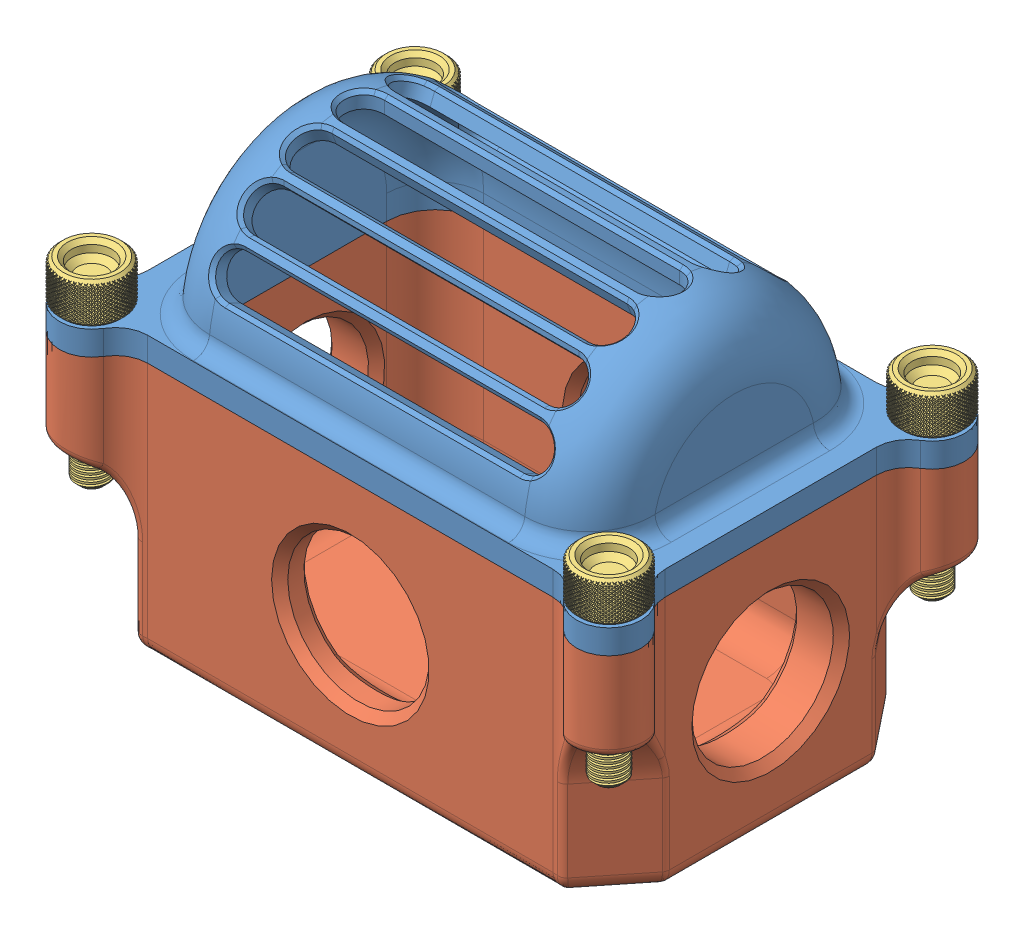
SolidWorks assembly Assem1, configuration Default. Lengths in mm.
Overall size (228.61 167.16 152.41).
6 component instances, 3 part files, 5 mates.
Components (placement in the parent):
- Housing_Top-1: Housing_Top [Default] at origin size (228.6 66.68 152.4)
- Housing_Bottom-1: Housing_Bottom [Default] x (1 0 0) z (0 0 -1) size (228.6 100.49 152.4)
- Knurled_Screw-1: Knurled_Screw [Default] at (-101.6 -12.7 63.5) size (25.41 76.38 25.41)
- Knurled_Screw-2: Knurled_Screw [Default] at (-101.6 -12.7 -63.5) size (25.41 76.38 25.41)
- Knurled_Screw-3: Knurled_Screw [Default] at (101.6 -12.7 63.5) size (25.41 76.38 25.41)
- Knurled_Screw-4: Knurled_Screw [Default] at (101.6 -12.7 -63.5) size (25.41 76.38 25.41)
Mates (geometry in assembly coordinates):
- ProfileCenter1: profile center anti-aligned: line of Housing_Bottom-1 through (-61.9125 0 -50.8) axis (1 0 0); line of Housing_Top-1 through (-61.9125 0 50.8) axis (1 0 0)
- ProfileCenter2: profile center aligned: circle of Housing_Top-1; circle of Knurled_Screw-1
- ProfileCenter3: profile center aligned: circle of Housing_Top-1; circle of Knurled_Screw-2
- ProfileCenter4: profile center anti-aligned: circle of Knurled_Screw-3; circle of Housing_Top-1
- ProfileCenter5: profile center anti-aligned: circle of Knurled_Screw-4; circle of Housing_Top-1
